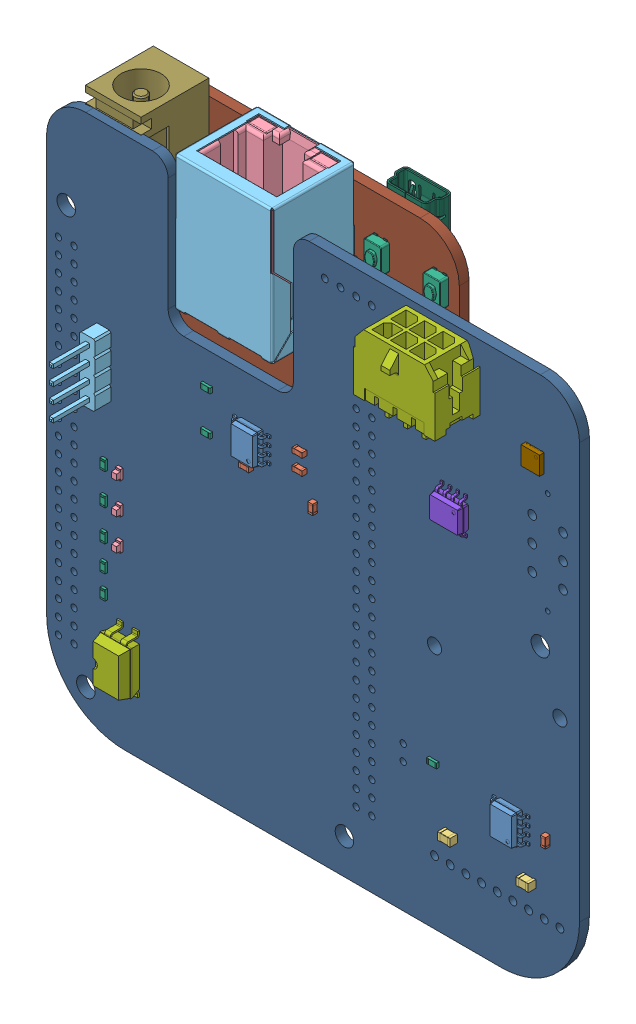
SolidWorks assembly 19-ELC-2700(Telemetry), configuration Default. Lengths in mm.
Overall size (86.37 89.7 26.61).
209 component instances, 25 part files, 7 mates.
Components (placement in the parent):
- 19-ELC-2700(Telemetry)(2)^19-ELC-2700(Telemetry)-1: 19-ELC-2700(Telemetry)(2)^19-ELC-2700(Telemetry) [Default] at origin size (86.37 86.37 11.54) (virtual)
  - SOIC-8_3.9x4.9mm_P1.27mm^19-ELC-2700(Telemetry)(2)_19-ELC-2700(Telemetry)-1: SOIC-8_3.9x4.9mm_P1.27mm^19-ELC-2700(Telemetry)(2)_19-ELC-2700(Telemetry) [Default] at (71.196 -52.05 1.65) x (-1 0 0) z (0 0 1) size (6 4.9 1.75) (virtual)
    - SOLID^SOIC-8_3.9x4.9mm_P1.27mm_19-ELC-2700(Telemetry)(2)_19-ELC-2700(Telemetry)-1: SOLID^SOIC-8_3.9x4.9mm_P1.27mm_19-ELC-2700(Telemetry)(2)_19-ELC-2700(Telemetry) [Default] at origin size (6 4.9 1.75) (virtual)
  - C_0603_1608Metric^19-ELC-2700(Telemetry)(2)_19-ELC-2700(Telemetry)-1: C_0603_1608Metric^19-ELC-2700(Telemetry)(2)_19-ELC-2700(Telemetry) [Default] at (70.561 -55.86 1.65) size (1.6 0.8 0.8) (virtual)
    - SOLID-0^C_0603_1608Metric_19-ELC-2700(Telemetry)(2)_19-ELC-2700(Telemetry)-1: SOLID-0^C_0603_1608Metric_19-ELC-2700(Telemetry)(2)_19-ELC-2700(Telemetry) [Default] at origin size (1.6 0.8 0.8) (virtual)
  - C_0603_1608Metric^19-ELC-2700(Telemetry)(2)_19-ELC-2700(Telemetry)-2: C_0603_1608Metric^19-ELC-2700(Telemetry)(2)_19-ELC-2700(Telemetry) [Default] at (79.211 -49.51 1.65) size (1.6 0.8 0.8) (virtual)
    - SOLID-0^C_0603_1608Metric_19-ELC-2700(Telemetry)(2)_19-ELC-2700(Telemetry)-1: SOLID-0^C_0603_1608Metric_19-ELC-2700(Telemetry)(2)_19-ELC-2700(Telemetry) [Default] at origin size (1.6 0.8 0.8) (virtual)
  - C_0603_1608Metric^19-ELC-2700(Telemetry)(2)_19-ELC-2700(Telemetry)-3: C_0603_1608Metric^19-ELC-2700(Telemetry)(2)_19-ELC-2700(Telemetry) [Default] at (79.211 -52.05 1.65) size (1.6 0.8 0.8) (virtual)
    - SOLID-0^C_0603_1608Metric_19-ELC-2700(Telemetry)(2)_19-ELC-2700(Telemetry)-1: SOLID-0^C_0603_1608Metric_19-ELC-2700(Telemetry)(2)_19-ELC-2700(Telemetry) [Default] at origin size (1.6 0.8 0.8) (virtual)
  - C_0603_1608Metric^19-ELC-2700(Telemetry)(2)_19-ELC-2700(Telemetry)-4: C_0603_1608Metric^19-ELC-2700(Telemetry)(2)_19-ELC-2700(Telemetry) [Default] at (81.356 -56.255 1.65) x (0 1 0) z (0 0 1) size (1.6 0.8 0.8) (virtual)
    - SOLID-0^C_0603_1608Metric_19-ELC-2700(Telemetry)(2)_19-ELC-2700(Telemetry)-1: SOLID-0^C_0603_1608Metric_19-ELC-2700(Telemetry)(2)_19-ELC-2700(Telemetry) [Default] at origin size (1.6 0.8 0.8) (virtual)
  - C_0805_2012Metric^19-ELC-2700(Telemetry)(2)_19-ELC-2700(Telemetry)-1: C_0805_2012Metric^19-ELC-2700(Telemetry)(2)_19-ELC-2700(Telemetry) [Default] at (116.145 -91.42 1.65) x (-1 0 0) z (0 0 1) size (2 1.25 1.25) (virtual)
    - SOLID-1^C_0805_2012Metric_19-ELC-2700(Telemetry)(2)_19-ELC-2700(Telemetry)-1: SOLID-1^C_0805_2012Metric_19-ELC-2700(Telemetry)(2)_19-ELC-2700(Telemetry) [Default] at origin size (2 1.25 1.25) (virtual)
  - C_0805_2012Metric^19-ELC-2700(Telemetry)(2)_19-ELC-2700(Telemetry)-2: C_0805_2012Metric^19-ELC-2700(Telemetry)(2)_19-ELC-2700(Telemetry) [Default] at (103.445 -91.42 1.65) size (2 1.25 1.25) (virtual)
    - SOLID-1^C_0805_2012Metric_19-ELC-2700(Telemetry)(2)_19-ELC-2700(Telemetry)-1: SOLID-1^C_0805_2012Metric_19-ELC-2700(Telemetry)(2)_19-ELC-2700(Telemetry) [Default] at origin size (2 1.25 1.25) (virtual)
  - C_0603_1608Metric^19-ELC-2700(Telemetry)(2)_19-ELC-2700(Telemetry)-5: C_0603_1608Metric^19-ELC-2700(Telemetry)(2)_19-ELC-2700(Telemetry) [Default] at (119.075 -84.195 1.65) x (0 1 0) z (0 0 1) size (1.6 0.8 0.8) (virtual)
    - SOLID-0^C_0603_1608Metric_19-ELC-2700(Telemetry)(2)_19-ELC-2700(Telemetry)-1: SOLID-0^C_0603_1608Metric_19-ELC-2700(Telemetry)(2)_19-ELC-2700(Telemetry) [Default] at origin size (1.6 0.8 0.8) (virtual)
  - LED_0603_1608Metric^19-ELC-2700(Telemetry)(2)_19-ELC-2700(Telemetry)-1: LED_0603_1608Metric^19-ELC-2700(Telemetry)(2)_19-ELC-2700(Telemetry) [Default] at (49.86 -67.29 1.65) x (0 1 0) z (0 0 1) size (1.6 0.8 1.1) (virtual)
    - SOLID-2^LED_0603_1608Metric_19-ELC-2700(Telemetry)(2)_19-ELC-2700(Telemetry)-1: SOLID-2^LED_0603_1608Metric_19-ELC-2700(Telemetry)(2)_19-ELC-2700(Telemetry) [Default] at origin size (1.6 0.8 1.1) (virtual)
  - LED_0603_1608Metric^19-ELC-2700(Telemetry)(2)_19-ELC-2700(Telemetry)-2: LED_0603_1608Metric^19-ELC-2700(Telemetry)(2)_19-ELC-2700(Telemetry) [Default] at (49.86 -72.37 1.65) x (0 1 0) z (0 0 1) size (1.6 0.8 1.1) (virtual)
    - SOLID-2^LED_0603_1608Metric_19-ELC-2700(Telemetry)(2)_19-ELC-2700(Telemetry)-1: SOLID-2^LED_0603_1608Metric_19-ELC-2700(Telemetry)(2)_19-ELC-2700(Telemetry) [Default] at origin size (1.6 0.8 1.1) (virtual)
  - LED_0603_1608Metric^19-ELC-2700(Telemetry)(2)_19-ELC-2700(Telemetry)-3: LED_0603_1608Metric^19-ELC-2700(Telemetry)(2)_19-ELC-2700(Telemetry) [Default] at (49.86 -77.45 1.65) x (0 1 0) z (0 0 1) size (1.6 0.8 1.1) (virtual)
    - SOLID-2^LED_0603_1608Metric_19-ELC-2700(Telemetry)(2)_19-ELC-2700(Telemetry)-1: SOLID-2^LED_0603_1608Metric_19-ELC-2700(Telemetry)(2)_19-ELC-2700(Telemetry) [Default] at origin size (1.6 0.8 1.1) (virtual)
  - PinHeader_1x04_P2.54mm_Vertical^19-ELC-2700(Telemetry)(2)_19-ELC-2700(Telemetry)-1: PinHeader_1x04_P2.54mm_Vertical^19-ELC-2700(Telemetry)(2)_19-ELC-2700(Telemetry) [Default] at (46.99 -57.15 1.65) x (-1 0 0) z (0 0 1) size (2.54 10.16 11.54) (virtual)
    - SOLID-3^PinHeader_1x04_P2.54mm_Vertical_19-ELC-2700(Telemetry)(2)_19-ELC-2700(Telemetry)-1: SOLID-3^PinHeader_1x04_P2.54mm_Vertical_19-ELC-2700(Telemetry)(2)_19-ELC-2700(Telemetry) [Default] at origin size (2.54 10.16 11.54) (virtual)
  - R_0603_1608Metric^19-ELC-2700(Telemetry)(2)_19-ELC-2700(Telemetry)-1: R_0603_1608Metric^19-ELC-2700(Telemetry)(2)_19-ELC-2700(Telemetry) [Default] at (63.971 -54.59 1.65) size (1.6 0.8 0.45) (virtual)
    - SOLID-4^R_0603_1608Metric_19-ELC-2700(Telemetry)(2)_19-ELC-2700(Telemetry)-1: SOLID-4^R_0603_1608Metric_19-ELC-2700(Telemetry)(2)_19-ELC-2700(Telemetry) [Default] at origin size (1.6 0.8 0.45) (virtual)
  - R_0603_1608Metric^19-ELC-2700(Telemetry)(2)_19-ELC-2700(Telemetry)-2: R_0603_1608Metric^19-ELC-2700(Telemetry)(2)_19-ELC-2700(Telemetry) [Default] at (63.971 -48.24 1.65) size (1.6 0.8 0.45) (virtual)
    - SOLID-4^R_0603_1608Metric_19-ELC-2700(Telemetry)(2)_19-ELC-2700(Telemetry)-1: SOLID-4^R_0603_1608Metric_19-ELC-2700(Telemetry)(2)_19-ELC-2700(Telemetry) [Default] at origin size (1.6 0.8 0.45) (virtual)
  - R_0603_1608Metric^19-ELC-2700(Telemetry)(2)_19-ELC-2700(Telemetry)-3: R_0603_1608Metric^19-ELC-2700(Telemetry)(2)_19-ELC-2700(Telemetry) [Default] at (47.32 -67.29 1.65) x (0 1 0) z (0 0 1) size (1.6 0.8 0.45) (virtual)
    - SOLID-4^R_0603_1608Metric_19-ELC-2700(Telemetry)(2)_19-ELC-2700(Telemetry)-1: SOLID-4^R_0603_1608Metric_19-ELC-2700(Telemetry)(2)_19-ELC-2700(Telemetry) [Default] at origin size (1.6 0.8 0.45) (virtual)
  - R_0603_1608Metric^19-ELC-2700(Telemetry)(2)_19-ELC-2700(Telemetry)-4: R_0603_1608Metric^19-ELC-2700(Telemetry)(2)_19-ELC-2700(Telemetry) [Default] at (47.32 -72.37 1.65) x (0 1 0) z (0 0 1) size (1.6 0.8 0.45) (virtual)
    - SOLID-4^R_0603_1608Metric_19-ELC-2700(Telemetry)(2)_19-ELC-2700(Telemetry)-1: SOLID-4^R_0603_1608Metric_19-ELC-2700(Telemetry)(2)_19-ELC-2700(Telemetry) [Default] at origin size (1.6 0.8 0.45) (virtual)
  - R_0603_1608Metric^19-ELC-2700(Telemetry)(2)_19-ELC-2700(Telemetry)-5: R_0603_1608Metric^19-ELC-2700(Telemetry)(2)_19-ELC-2700(Telemetry) [Default] at (47.32 -77.45 1.65) x (0 1 0) z (0 0 1) size (1.6 0.8 0.45) (virtual)
    - SOLID-4^R_0603_1608Metric_19-ELC-2700(Telemetry)(2)_19-ELC-2700(Telemetry)-1: SOLID-4^R_0603_1608Metric_19-ELC-2700(Telemetry)(2)_19-ELC-2700(Telemetry) [Default] at origin size (1.6 0.8 0.45) (virtual)
  - R_0603_1608Metric^19-ELC-2700(Telemetry)(2)_19-ELC-2700(Telemetry)-6: R_0603_1608Metric^19-ELC-2700(Telemetry)(2)_19-ELC-2700(Telemetry) [Default] at (47.32 -85.465 1.65) x (0 1 0) z (0 0 1) size (1.6 0.8 0.45) (virtual)
    - SOLID-4^R_0603_1608Metric_19-ELC-2700(Telemetry)(2)_19-ELC-2700(Telemetry)-1: SOLID-4^R_0603_1608Metric_19-ELC-2700(Telemetry)(2)_19-ELC-2700(Telemetry) [Default] at origin size (1.6 0.8 0.45) (virtual)
  - R_0603_1608Metric^19-ELC-2700(Telemetry)(2)_19-ELC-2700(Telemetry)-7: R_0603_1608Metric^19-ELC-2700(Telemetry)(2)_19-ELC-2700(Telemetry) [Default] at (47.32 -81.655 1.65) x (0 1 0) z (0 0 1) size (1.6 0.8 0.45) (virtual)
    - SOLID-4^R_0603_1608Metric_19-ELC-2700(Telemetry)(2)_19-ELC-2700(Telemetry)-1: SOLID-4^R_0603_1608Metric_19-ELC-2700(Telemetry)(2)_19-ELC-2700(Telemetry) [Default] at origin size (1.6 0.8 0.45) (virtual)
  - R_0603_1608Metric^19-ELC-2700(Telemetry)(2)_19-ELC-2700(Telemetry)-8: R_0603_1608Metric^19-ELC-2700(Telemetry)(2)_19-ELC-2700(Telemetry) [Default] at (100.66 -82.53 1.65) x (-1 0 0) z (0 0 1) size (1.6 0.8 0.45) (virtual)
    - SOLID-4^R_0603_1608Metric_19-ELC-2700(Telemetry)(2)_19-ELC-2700(Telemetry)-1: SOLID-4^R_0603_1608Metric_19-ELC-2700(Telemetry)(2)_19-ELC-2700(Telemetry) [Default] at origin size (1.6 0.8 0.45) (virtual)
  - SMDIP-4_W9.53mm^19-ELC-2700(Telemetry)(2)_19-ELC-2700(Telemetry)-1: SMDIP-4_W9.53mm^19-ELC-2700(Telemetry)(2)_19-ELC-2700(Telemetry) [Default] at (51.13 -92.69 1.65) x (0 1 0) z (0 0 1) size (9.32 4.93 3.68) (virtual)
    - SOLID-5^SMDIP-4_W9.53mm_19-ELC-2700(Telemetry)(2)_19-ELC-2700(Telemetry)-1: SOLID-5^SMDIP-4_W9.53mm_19-ELC-2700(Telemetry)(2)_19-ELC-2700(Telemetry) [Default] at origin size (9.32 4.93 3.68) (virtual)
  - SOIC-8_3.9x4.9mm_P1.27mm^19-ELC-2700(Telemetry)(2)_19-ELC-2700(Telemetry)-2: SOIC-8_3.9x4.9mm_P1.27mm^19-ELC-2700(Telemetry)(2)_19-ELC-2700(Telemetry) [Default] at (113.2 -84.435 1.65) x (-1 0 0) z (0 0 1) size (6 4.9 1.75) (virtual)
    - SOLID^SOIC-8_3.9x4.9mm_P1.27mm_19-ELC-2700(Telemetry)(2)_19-ELC-2700(Telemetry)-1: SOLID^SOIC-8_3.9x4.9mm_P1.27mm_19-ELC-2700(Telemetry)(2)_19-ELC-2700(Telemetry) [Default] at origin size (6 4.9 1.75) (virtual)
  - SOIC-8-1EP_3.9x4.9mm_P1.27mm_EP2.35x2.35mm^19-ELC-2700(Telemetry)(2)_19-ELC-2700(Telemetry)-1: SOIC-8-1EP_3.9x4.9mm_P1.27mm_EP2.35x2.35mm^19-ELC-2700(Telemetry)(2)_19-ELC-2700(Telemetry) [Default] at (103.942 -45.37 1.65) x (0 -1 0) z (0 0 1) size (6 4.9 1.75) (virtual)
    - SOLID-6^SOIC-8-1EP_3.9x4.9mm_P1.27mm_EP2.35x2.35mm_19-ELC-2700(Telemetry)(2)_19-ELC-2700(Telemetry)-1: SOLID-6^SOIC-8-1EP_3.9x4.9mm_P1.27mm_EP2.35x2.35mm_19-ELC-2700(Telemetry)(2)_19-ELC-2700(Telemetry) [Default] at origin size (6 4.9 1.75) (virtual)
  - DFN-12-1EP_3x3mm_P0.45mm_EP1.66x2.38mm^19-ELC-2700(Telemetry)(2)_19-ELC-2700(Telemetry)-1: DFN-12-1EP_3x3mm_P0.45mm_EP1.66x2.38mm^19-ELC-2700(Telemetry)(2)_19-ELC-2700(Telemetry) [Default] at (117.003 -31.687 1.65) x (0 -1 0) z (0 0 1) size (3 2.98 0.77) (virtual)
    - SOLID-7^DFN-12-1EP_3x3mm_P0.45mm_EP1.66x2.38mm_19-ELC-2700(Telemetry)(2)_19-ELC-2700(Telemetry)-1: SOLID-7^DFN-12-1EP_3x3mm_P0.45mm_EP1.66x2.38mm_19-ELC-2700(Telemetry)(2)_19-ELC-2700(Telemetry) [Default] at origin size (3 2.98 0.77) (virtual)
  - COMPOUND^19-ELC-2700(Telemetry)(2)_19-ELC-2700(Telemetry)-1: COMPOUND^19-ELC-2700(Telemetry)(2)_19-ELC-2700(Telemetry) [Default] at origin size (86.37 86.37 1.67) (virtual)
- BeagleBone-Black PCBA-1: BeagleBone-Black PCBA [Default] at (65.1 -62.845 -11.4618) x (0 -1 0) z (-1 0 0) size (89.7 19.07 54.61)
  - BEAGLEBONE_BLACK Board-1: BEAGLEBONE_BLACK Board [Default] at origin size (86.36 1.59 54.61)
  - PG-002A-1: PG-002A [Default] at (-45.704 7.2938 17.779) x (-1 0 0) z (0 0 -1) size (14.4 14.5 9.4)
  - SSHS-123-D-02-GT-LF-1: SSHS-123-D-02-GT-LF [Default] at (-23.495 5.1069 25.4) x (0 0 -1) z (1 0 0) size (5.03 11.05 58.42)
    - SSH-1-D-50-1: SSH-1-D-50 [Default] at origin size (5.03 8.51 2.54)
    - C-025-02-T-1: C-025-02-T [Default] at (2.54 -0.3048 0) x (0 0 1) z (1 0 0) size (1.99 9.43 0.41)
    - C-025-02-T-2: C-025-02-T [Default] at (0 -0.3048 0) x (0 0 -1) z (-1 0 0) size (1.99 9.43 0.41)
    - C-025-02-T-3: C-025-02-T [Default] at (2.54 -0.3048 2.54) x (0 0 1) z (1 0 0) size (1.99 9.43 0.41)
    - C-025-02-T-4: C-025-02-T [Default] at (2.54 -0.3048 5.08) x (0 0 1) z (1 0 0) size (1.99 9.43 0.41)
    - C-025-02-T-5: C-025-02-T [Default] at (2.54 -0.3048 7.62) x (0 0 1) z (1 0 0) size (1.99 9.43 0.41)
    - C-025-02-T-6: C-025-02-T [Default] at (2.54 -0.3048 10.16) x (0 0 1) z (1 0 0) size (1.99 9.43 0.41)
    - C-025-02-T-7: C-025-02-T [Default] at (2.54 -0.3048 12.7) x (0 0 1) z (1 0 0) size (1.99 9.43 0.41)
    - C-025-02-T-8: C-025-02-T [Default] at (2.54 -0.3048 15.24) x (0 0 1) z (1 0 0) size (1.99 9.43 0.41)
    - C-025-02-T-9: C-025-02-T [Default] at (2.54 -0.3048 17.78) x (0 0 1) z (1 0 0) size (1.99 9.43 0.41)
    - C-025-02-T-10: C-025-02-T [Default] at (2.54 -0.3048 20.32) x (0 0 1) z (1 0 0) size (1.99 9.43 0.41)
    - C-025-02-T-11: C-025-02-T [Default] at (2.54 -0.3048 22.86) x (0 0 1) z (1 0 0) size (1.99 9.43 0.41)
    - C-025-02-T-12: C-025-02-T [Default] at (2.54 -0.3048 25.4) x (0 0 1) z (1 0 0) size (1.99 9.43 0.41)
    - C-025-02-T-13: C-025-02-T [Default] at (2.54 -0.3048 27.94) x (0 0 1) z (1 0 0) size (1.99 9.43 0.41)
    - C-025-02-T-14: C-025-02-T [Default] at (2.54 -0.3048 30.48) x (0 0 1) z (1 0 0) size (1.99 9.43 0.41)
    - C-025-02-T-15: C-025-02-T [Default] at (2.54 -0.3048 33.02) x (0 0 1) z (1 0 0) size (1.99 9.43 0.41)
    - C-025-02-T-16: C-025-02-T [Default] at (2.54 -0.3048 35.56) x (0 0 1) z (1 0 0) size (1.99 9.43 0.41)
    - C-025-02-T-17: C-025-02-T [Default] at (2.54 -0.3048 38.1) x (0 0 1) z (1 0 0) size (1.99 9.43 0.41)
    - C-025-02-T-18: C-025-02-T [Default] at (2.54 -0.3048 40.64) x (0 0 1) z (1 0 0) size (1.99 9.43 0.41)
    - C-025-02-T-19: C-025-02-T [Default] at (2.54 -0.3048 43.18) x (0 0 1) z (1 0 0) size (1.99 9.43 0.41)
    - C-025-02-T-20: C-025-02-T [Default] at (2.54 -0.3048 45.72) x (0 0 1) z (1 0 0) size (1.99 9.43 0.41)
    - C-025-02-T-21: C-025-02-T [Default] at (2.54 -0.3048 48.26) x (0 0 1) z (1 0 0) size (1.99 9.43 0.41)
    - C-025-02-T-22: C-025-02-T [Default] at (2.54 -0.3048 50.8) x (0 0 1) z (1 0 0) size (1.99 9.43 0.41)
    - C-025-02-T-23: C-025-02-T [Default] at (2.54 -0.3048 53.34) x (0 0 1) z (1 0 0) size (1.99 9.43 0.41)
    - C-025-02-T-24: C-025-02-T [Default] at (2.54 -0.3048 55.88) x (0 0 1) z (1 0 0) size (1.99 9.43 0.41)
    - C-025-02-T-25: C-025-02-T [Default] at (0 -0.3048 2.54) x (0 0 -1) z (-1 0 0) size (1.99 9.43 0.41)
    - C-025-02-T-26: C-025-02-T [Default] at (0 -0.3048 5.08) x (0 0 -1) z (-1 0 0) size (1.99 9.43 0.41)
    - C-025-02-T-27: C-025-02-T [Default] at (0 -0.3048 7.62) x (0 0 -1) z (-1 0 0) size (1.99 9.43 0.41)
    - C-025-02-T-28: C-025-02-T [Default] at (0 -0.3048 10.16) x (0 0 -1) z (-1 0 0) size (1.99 9.43 0.41)
    - C-025-02-T-29: C-025-02-T [Default] at (0 -0.3048 12.7) x (0 0 -1) z (-1 0 0) size (1.99 9.43 0.41)
    - C-025-02-T-30: C-025-02-T [Default] at (0 -0.3048 15.24) x (0 0 -1) z (-1 0 0) size (1.99 9.43 0.41)
    - C-025-02-T-31: C-025-02-T [Default] at (0 -0.3048 17.78) x (0 0 -1) z (-1 0 0) size (1.99 9.43 0.41)
    - C-025-02-T-32: C-025-02-T [Default] at (0 -0.3048 20.32) x (0 0 -1) z (-1 0 0) size (1.99 9.43 0.41)
    - C-025-02-T-33: C-025-02-T [Default] at (0 -0.3048 22.86) x (0 0 -1) z (-1 0 0) size (1.99 9.43 0.41)
    - C-025-02-T-34: C-025-02-T [Default] at (0 -0.3048 25.4) x (0 0 -1) z (-1 0 0) size (1.99 9.43 0.41)
    - C-025-02-T-35: C-025-02-T [Default] at (0 -0.3048 27.94) x (0 0 -1) z (-1 0 0) size (1.99 9.43 0.41)
    - C-025-02-T-36: C-025-02-T [Default] at (0 -0.3048 30.48) x (0 0 -1) z (-1 0 0) size (1.99 9.43 0.41)
    - C-025-02-T-37: C-025-02-T [Default] at (0 -0.3048 33.02) x (0 0 -1) z (-1 0 0) size (1.99 9.43 0.41)
    - C-025-02-T-38: C-025-02-T [Default] at (0 -0.3048 35.56) x (0 0 -1) z (-1 0 0) size (1.99 9.43 0.41)
    - C-025-02-T-39: C-025-02-T [Default] at (0 -0.3048 38.1) x (0 0 -1) z (-1 0 0) size (1.99 9.43 0.41)
    - C-025-02-T-40: C-025-02-T [Default] at (0 -0.3048 40.64) x (0 0 -1) z (-1 0 0) size (1.99 9.43 0.41)
    - C-025-02-T-41: C-025-02-T [Default] at (0 -0.3048 43.18) x (0 0 -1) z (-1 0 0) size (1.99 9.43 0.41)
    - C-025-02-T-42: C-025-02-T [Default] at (0 -0.3048 45.72) x (0 0 -1) z (-1 0 0) size (1.99 9.43 0.41)
    - C-025-02-T-43: C-025-02-T [Default] at (0 -0.3048 48.26) x (0 0 -1) z (-1 0 0) size (1.99 9.43 0.41)
    - C-025-02-T-44: C-025-02-T [Default] at (0 -0.3048 50.8) x (0 0 -1) z (-1 0 0) size (1.99 9.43 0.41)
    - C-025-02-T-45: C-025-02-T [Default] at (0 -0.3048 53.34) x (0 0 -1) z (-1 0 0) size (1.99 9.43 0.41)
    - C-025-02-T-46: C-025-02-T [Default] at (0 -0.3048 55.88) x (0 0 -1) z (-1 0 0) size (1.99 9.43 0.41)
    - SSH-1-D-50-2: SSH-1-D-50 [Default] at (0 0 2.54) size (5.03 8.51 2.54)
    - SSH-1-D-50-3: SSH-1-D-50 [Default] at (0 0 5.08) size (5.03 8.51 2.54)
    - SSH-1-D-50-4: SSH-1-D-50 [Default] at (0 0 7.62) size (5.03 8.51 2.54)
    - SSH-1-D-50-5: SSH-1-D-50 [Default] at (0 0 10.16) size (5.03 8.51 2.54)
    - SSH-1-D-50-6: SSH-1-D-50 [Default] at (0 0 12.7) size (5.03 8.51 2.54)
    - SSH-1-D-50-7: SSH-1-D-50 [Default] at (0 0 15.24) size (5.03 8.51 2.54)
    - SSH-1-D-50-8: SSH-1-D-50 [Default] at (0 0 17.78) size (5.03 8.51 2.54)
    - SSH-1-D-50-9: SSH-1-D-50 [Default] at (0 0 20.32) size (5.03 8.51 2.54)
    - SSH-1-D-50-10: SSH-1-D-50 [Default] at (0 0 22.86) size (5.03 8.51 2.54)
    - SSH-1-D-50-11: SSH-1-D-50 [Default] at (0 0 25.4) size (5.03 8.51 2.54)
    - SSH-1-D-50-12: SSH-1-D-50 [Default] at (0 0 27.94) size (5.03 8.51 2.54)
    - SSH-1-D-50-13: SSH-1-D-50 [Default] at (0 0 30.48) size (5.03 8.51 2.54)
    - SSH-1-D-50-14: SSH-1-D-50 [Default] at (0 0 33.02) size (5.03 8.51 2.54)
    - SSH-1-D-50-15: SSH-1-D-50 [Default] at (0 0 35.56) size (5.03 8.51 2.54)
    - SSH-1-D-50-16: SSH-1-D-50 [Default] at (0 0 38.1) size (5.03 8.51 2.54)
    - SSH-1-D-50-17: SSH-1-D-50 [Default] at (0 0 40.64) size (5.03 8.51 2.54)
    - SSH-1-D-50-18: SSH-1-D-50 [Default] at (0 0 43.18) size (5.03 8.51 2.54)
    - SSH-1-D-50-19: SSH-1-D-50 [Default] at (0 0 45.72) size (5.03 8.51 2.54)
    - SSH-1-D-50-20: SSH-1-D-50 [Default] at (0 0 48.26) size (5.03 8.51 2.54)
    - SSH-1-D-50-21: SSH-1-D-50 [Default] at (0 0 50.8) size (5.03 8.51 2.54)
    - SSH-1-D-50-22: SSH-1-D-50 [Default] at (0 0 53.34) size (5.03 8.51 2.54)
    - SSH-1-D-50-23: SSH-1-D-50 [Default] at (0 0 55.88) size (5.03 8.51 2.54)
  - SSHS-123-D-02-GT-LF-2: SSHS-123-D-02-GT-LF [Default] at (-23.495 5.0482 -22.86) x (0 0 -1) z (1 0 0) size (5.03 11.05 58.42)
    - SSH-1-D-50-1: SSH-1-D-50 [Default] at origin size (5.03 8.51 2.54)
    - C-025-02-T-1: C-025-02-T [Default] at (2.54 -0.3048 0) x (0 0 1) z (1 0 0) size (1.99 9.43 0.41)
    - C-025-02-T-2: C-025-02-T [Default] at (0 -0.3048 0) x (0 0 -1) z (-1 0 0) size (1.99 9.43 0.41)
    - C-025-02-T-3: C-025-02-T [Default] at (2.54 -0.3048 2.54) x (0 0 1) z (1 0 0) size (1.99 9.43 0.41)
    - C-025-02-T-4: C-025-02-T [Default] at (2.54 -0.3048 5.08) x (0 0 1) z (1 0 0) size (1.99 9.43 0.41)
    - C-025-02-T-5: C-025-02-T [Default] at (2.54 -0.3048 7.62) x (0 0 1) z (1 0 0) size (1.99 9.43 0.41)
    - C-025-02-T-6: C-025-02-T [Default] at (2.54 -0.3048 10.16) x (0 0 1) z (1 0 0) size (1.99 9.43 0.41)
    - C-025-02-T-7: C-025-02-T [Default] at (2.54 -0.3048 12.7) x (0 0 1) z (1 0 0) size (1.99 9.43 0.41)
    - C-025-02-T-8: C-025-02-T [Default] at (2.54 -0.3048 15.24) x (0 0 1) z (1 0 0) size (1.99 9.43 0.41)
    - C-025-02-T-9: C-025-02-T [Default] at (2.54 -0.3048 17.78) x (0 0 1) z (1 0 0) size (1.99 9.43 0.41)
    - C-025-02-T-10: C-025-02-T [Default] at (2.54 -0.3048 20.32) x (0 0 1) z (1 0 0) size (1.99 9.43 0.41)
    - C-025-02-T-11: C-025-02-T [Default] at (2.54 -0.3048 22.86) x (0 0 1) z (1 0 0) size (1.99 9.43 0.41)
    - C-025-02-T-12: C-025-02-T [Default] at (2.54 -0.3048 25.4) x (0 0 1) z (1 0 0) size (1.99 9.43 0.41)
    - C-025-02-T-13: C-025-02-T [Default] at (2.54 -0.3048 27.94) x (0 0 1) z (1 0 0) size (1.99 9.43 0.41)
    - C-025-02-T-14: C-025-02-T [Default] at (2.54 -0.3048 30.48) x (0 0 1) z (1 0 0) size (1.99 9.43 0.41)
    - C-025-02-T-15: C-025-02-T [Default] at (2.54 -0.3048 33.02) x (0 0 1) z (1 0 0) size (1.99 9.43 0.41)
    - C-025-02-T-16: C-025-02-T [Default] at (2.54 -0.3048 35.56) x (0 0 1) z (1 0 0) size (1.99 9.43 0.41)
    - C-025-02-T-17: C-025-02-T [Default] at (2.54 -0.3048 38.1) x (0 0 1) z (1 0 0) size (1.99 9.43 0.41)
    - C-025-02-T-18: C-025-02-T [Default] at (2.54 -0.3048 40.64) x (0 0 1) z (1 0 0) size (1.99 9.43 0.41)
    - C-025-02-T-19: C-025-02-T [Default] at (2.54 -0.3048 43.18) x (0 0 1) z (1 0 0) size (1.99 9.43 0.41)
    - C-025-02-T-20: C-025-02-T [Default] at (2.54 -0.3048 45.72) x (0 0 1) z (1 0 0) size (1.99 9.43 0.41)
    - C-025-02-T-21: C-025-02-T [Default] at (2.54 -0.3048 48.26) x (0 0 1) z (1 0 0) size (1.99 9.43 0.41)
    - C-025-02-T-22: C-025-02-T [Default] at (2.54 -0.3048 50.8) x (0 0 1) z (1 0 0) size (1.99 9.43 0.41)
    - C-025-02-T-23: C-025-02-T [Default] at (2.54 -0.3048 53.34) x (0 0 1) z (1 0 0) size (1.99 9.43 0.41)
    - C-025-02-T-24: C-025-02-T [Default] at (2.54 -0.3048 55.88) x (0 0 1) z (1 0 0) size (1.99 9.43 0.41)
    - C-025-02-T-25: C-025-02-T [Default] at (0 -0.3048 2.54) x (0 0 -1) z (-1 0 0) size (1.99 9.43 0.41)
    - C-025-02-T-26: C-025-02-T [Default] at (0 -0.3048 5.08) x (0 0 -1) z (-1 0 0) size (1.99 9.43 0.41)
    - C-025-02-T-27: C-025-02-T [Default] at (0 -0.3048 7.62) x (0 0 -1) z (-1 0 0) size (1.99 9.43 0.41)
    - C-025-02-T-28: C-025-02-T [Default] at (0 -0.3048 10.16) x (0 0 -1) z (-1 0 0) size (1.99 9.43 0.41)
    - C-025-02-T-29: C-025-02-T [Default] at (0 -0.3048 12.7) x (0 0 -1) z (-1 0 0) size (1.99 9.43 0.41)
    - C-025-02-T-30: C-025-02-T [Default] at (0 -0.3048 15.24) x (0 0 -1) z (-1 0 0) size (1.99 9.43 0.41)
    - C-025-02-T-31: C-025-02-T [Default] at (0 -0.3048 17.78) x (0 0 -1) z (-1 0 0) size (1.99 9.43 0.41)
    - C-025-02-T-32: C-025-02-T [Default] at (0 -0.3048 20.32) x (0 0 -1) z (-1 0 0) size (1.99 9.43 0.41)
    - C-025-02-T-33: C-025-02-T [Default] at (0 -0.3048 22.86) x (0 0 -1) z (-1 0 0) size (1.99 9.43 0.41)
    - C-025-02-T-34: C-025-02-T [Default] at (0 -0.3048 25.4) x (0 0 -1) z (-1 0 0) size (1.99 9.43 0.41)
    - C-025-02-T-35: C-025-02-T [Default] at (0 -0.3048 27.94) x (0 0 -1) z (-1 0 0) size (1.99 9.43 0.41)
    - C-025-02-T-36: C-025-02-T [Default] at (0 -0.3048 30.48) x (0 0 -1) z (-1 0 0) size (1.99 9.43 0.41)
    - C-025-02-T-37: C-025-02-T [Default] at (0 -0.3048 33.02) x (0 0 -1) z (-1 0 0) size (1.99 9.43 0.41)
    - C-025-02-T-38: C-025-02-T [Default] at (0 -0.3048 35.56) x (0 0 -1) z (-1 0 0) size (1.99 9.43 0.41)
    - C-025-02-T-39: C-025-02-T [Default] at (0 -0.3048 38.1) x (0 0 -1) z (-1 0 0) size (1.99 9.43 0.41)
    - C-025-02-T-40: C-025-02-T [Default] at (0 -0.3048 40.64) x (0 0 -1) z (-1 0 0) size (1.99 9.43 0.41)
    - C-025-02-T-41: C-025-02-T [Default] at (0 -0.3048 43.18) x (0 0 -1) z (-1 0 0) size (1.99 9.43 0.41)
    - C-025-02-T-42: C-025-02-T [Default] at (0 -0.3048 45.72) x (0 0 -1) z (-1 0 0) size (1.99 9.43 0.41)
    - C-025-02-T-43: C-025-02-T [Default] at (0 -0.3048 48.26) x (0 0 -1) z (-1 0 0) size (1.99 9.43 0.41)
    - C-025-02-T-44: C-025-02-T [Default] at (0 -0.3048 50.8) x (0 0 -1) z (-1 0 0) size (1.99 9.43 0.41)
    - C-025-02-T-45: C-025-02-T [Default] at (0 -0.3048 53.34) x (0 0 -1) z (-1 0 0) size (1.99 9.43 0.41)
    - C-025-02-T-46: C-025-02-T [Default] at (0 -0.3048 55.88) x (0 0 -1) z (-1 0 0) size (1.99 9.43 0.41)
    - SSH-1-D-50-2: SSH-1-D-50 [Default] at (0 0 2.54) size (5.03 8.51 2.54)
    - SSH-1-D-50-3: SSH-1-D-50 [Default] at (0 0 5.08) size (5.03 8.51 2.54)
    - SSH-1-D-50-4: SSH-1-D-50 [Default] at (0 0 7.62) size (5.03 8.51 2.54)
    - SSH-1-D-50-5: SSH-1-D-50 [Default] at (0 0 10.16) size (5.03 8.51 2.54)
    - SSH-1-D-50-6: SSH-1-D-50 [Default] at (0 0 12.7) size (5.03 8.51 2.54)
    - SSH-1-D-50-7: SSH-1-D-50 [Default] at (0 0 15.24) size (5.03 8.51 2.54)
    - SSH-1-D-50-8: SSH-1-D-50 [Default] at (0 0 17.78) size (5.03 8.51 2.54)
    - SSH-1-D-50-9: SSH-1-D-50 [Default] at (0 0 20.32) size (5.03 8.51 2.54)
    - SSH-1-D-50-10: SSH-1-D-50 [Default] at (0 0 22.86) size (5.03 8.51 2.54)
    - SSH-1-D-50-11: SSH-1-D-50 [Default] at (0 0 25.4) size (5.03 8.51 2.54)
    - SSH-1-D-50-12: SSH-1-D-50 [Default] at (0 0 27.94) size (5.03 8.51 2.54)
    - SSH-1-D-50-13: SSH-1-D-50 [Default] at (0 0 30.48) size (5.03 8.51 2.54)
    - SSH-1-D-50-14: SSH-1-D-50 [Default] at (0 0 33.02) size (5.03 8.51 2.54)
    - SSH-1-D-50-15: SSH-1-D-50 [Default] at (0 0 35.56) size (5.03 8.51 2.54)
    - SSH-1-D-50-16: SSH-1-D-50 [Default] at (0 0 38.1) size (5.03 8.51 2.54)
    - SSH-1-D-50-17: SSH-1-D-50 [Default] at (0 0 40.64) size (5.03 8.51 2.54)
    - SSH-1-D-50-18: SSH-1-D-50 [Default] at (0 0 43.18) size (5.03 8.51 2.54)
    - SSH-1-D-50-19: SSH-1-D-50 [Default] at (0 0 45.72) size (5.03 8.51 2.54)
    - SSH-1-D-50-20: SSH-1-D-50 [Default] at (0 0 48.26) size (5.03 8.51 2.54)
    - SSH-1-D-50-21: SSH-1-D-50 [Default] at (0 0 50.8) size (5.03 8.51 2.54)
    - SSH-1-D-50-22: SSH-1-D-50 [Default] at (0 0 53.34) size (5.03 8.51 2.54)
    - SSH-1-D-50-23: SSH-1-D-50 [Default] at (0 0 55.88) size (5.03 8.51 2.54)
  - UX60SC-MB-5ST-1: UX60SC-MB-5ST [Default] at (-63.0947 -3.2937 -14.5842) x (0 0 -1) z (0 -1 0) size (9.81 7.01 3.99)
    - UX60SC-MB-5ST-1: UX60SC-MB-5ST [Default] at (2.4471 21.2893 1.05) x (-1 0 0) z (0 0 1) size (9.81 7.01 3.99)
  - 10118241-001rlf_asm-1: 10118241-001rlf_asm [Default] at (43.88 -3.6937 2.1589) x (0 0 1) z (1 0 0) size (8.91 3.53 7.5)
    - MSBR-1-1: MSBR-1 [Default] at origin size (5.9 2.78 6.03)
    - MSBR-2-1: MSBR-2 [Default] at origin size (5.5 0.08 3.5)
    - _HDMI_D_TYPE_RECEPTACLE-1: _HDMI_D_TYPE_RECEPTACLE [Default] at origin size (8.91 3.45 7.5)
  - 87520-0010BLF-1: 87520-0010BLF [Default] at (29.1502 4.3468 10.4878) x (0 0 -1) z (1 0 0) size (14.5 10.48 14)
  - SCHA5B0200-1: SCHA5B0200 [Default] at (28.23 -0.7937 -10.405) x (0 0 1) z (0 -1 0) size (15.01 15.51 1.52)
  - i68000-x06-1: i68000-x06 [Default] at (-0.635 0.9969 19.685) size (15.24 10.79 2.41)
  - LPJ0011BBNL - RJ45-1: LPJ0011BBNL - RJ45 [Default] at (-34.895 7.5438 -2.535) x (0 0 1) z (-1 0 0) size (15.88 16.55 21.84)
    - LINK LP0011BBNL Internal-1: LINK LP0011BBNL Internal [Default] x (-1 0 0) z (0 0 1) size (15.48 16.35 21.44)
    - LINK LP0011BBNL-1: LINK LP0011BBNL [Default] at (0 0 0.03) x (-1 0 0) z (0 -1 0) size (15.88 21.84 16.25)
  - KMR231GLFS-1: KMR231GLFS [Default] at (32.3628 1.4938 -15.8975) size (4.6 1.9 2.8)
  - KMR231GLFS-2: KMR231GLFS [Default] at (-35.1378 1.4938 -14.5984) size (4.6 1.9 2.8)
  - KMR231GLFS-3: KMR231GLFS [Default] at (-35.1378 1.4938 -24.1858) size (4.6 1.9 2.8)
- MicroFit PCB Mount 6 Pin TH Right Angle 430450600-2: MicroFit PCB Mount 6 Pin TH Right Angle 430450600 [Default] at (101.495 -25.22 5.535) x (-1 0 0) z (0 1 0) size (13.15 11.95 12.24)
Mates (geometry in assembly coordinates):
- Parallel2: parallel: plane of 19-ELC-2700(Telemetry)(2)^19-ELC-2700(Telemetry)-1/COMPOUND^19-ELC-2700(Telemetry)(2)_19-ELC-2700(Telemetry)-1 through (75.26 -43.16 0) normal (0 0 -1); plane of BeagleBone-Black PCBA-1/SSHS-123-D-02-GT-LF-1/SSH-1-D-50-10 through (38.4554 -63.48 -2.1004) normal (0 0 1)
- Concentric1: concentric: cylinder of 19-ELC-2700(Telemetry)(2)^19-ELC-2700(Telemetry)-1/COMPOUND^19-ELC-2700(Telemetry)(2)_19-ELC-2700(Telemetry)-1 through (40.97 -34.27 -0.8) axis (0 0 1) radius 1.5; cylinder of BeagleBone-Black PCBA-1/BEAGLEBONE_BLACK Board-1 through (40.97 -34.27 -10.668) axis (0 0 -1) radius 1.5875
- Concentric2: concentric: cylinder of 19-ELC-2700(Telemetry)(2)^19-ELC-2700(Telemetry)-1/COMPOUND^19-ELC-2700(Telemetry)(2)_19-ELC-2700(Telemetry)-1 through (86.055 -100.31 -0.8) axis (0 0 1) radius 1.5; cylinder of BeagleBone-Black PCBA-1/BEAGLEBONE_BLACK Board-1 through (86.055 -100.31 -10.668) axis (0 0 -1) radius 1.5875
- Distance1: distance = 10.668 mm: plane of BeagleBone-Black PCBA-1/BEAGLEBONE_BLACK Board-1 through (65.1 -62.845 -10.668) normal (0 0 1); plane of 19-ELC-2700(Telemetry)(2)^19-ELC-2700(Telemetry)-1/COMPOUND^19-ELC-2700(Telemetry)(2)_19-ELC-2700(Telemetry)-1 through (75.26 -43.16 0) normal (0 0 -1)
- Concentric3: concentric: cylinder of 19-ELC-2700(Telemetry)(2)^19-ELC-2700(Telemetry)-1/COMPOUND^19-ELC-2700(Telemetry)(2)_19-ELC-2700(Telemetry)-1 through (101.12 -24.87 -0.8) axis (0 0 1) radius 1.55; cylinder of MicroFit PCB Mount 6 Pin TH Right Angle 430450600-2 through (101.12 -24.87 2.284) axis (0 0 -1) radius 1.1
- Coincident6: coincident: plane of 19-ELC-2700(Telemetry)(2)^19-ELC-2700(Telemetry)-1/COMPOUND^19-ELC-2700(Telemetry)(2)_19-ELC-2700(Telemetry)-1 through (75.26 -43.16 1.6) normal (0 0 1); plane of MicroFit PCB Mount 6 Pin TH Right Angle 430450600-2 through (107.82 -28.18 1.6) normal (0 0 -1)
- Parallel3: parallel: plane of 19-ELC-2700(Telemetry)(2)^19-ELC-2700(Telemetry)-1/COMPOUND^19-ELC-2700(Telemetry)(2)_19-ELC-2700(Telemetry)-1 through (117.805 -19.665 0) normal (0 1 0); plane of MicroFit PCB Mount 6 Pin TH Right Angle 430450600-2 through (107.82 -20.27 8.97) normal (0 1 0)
